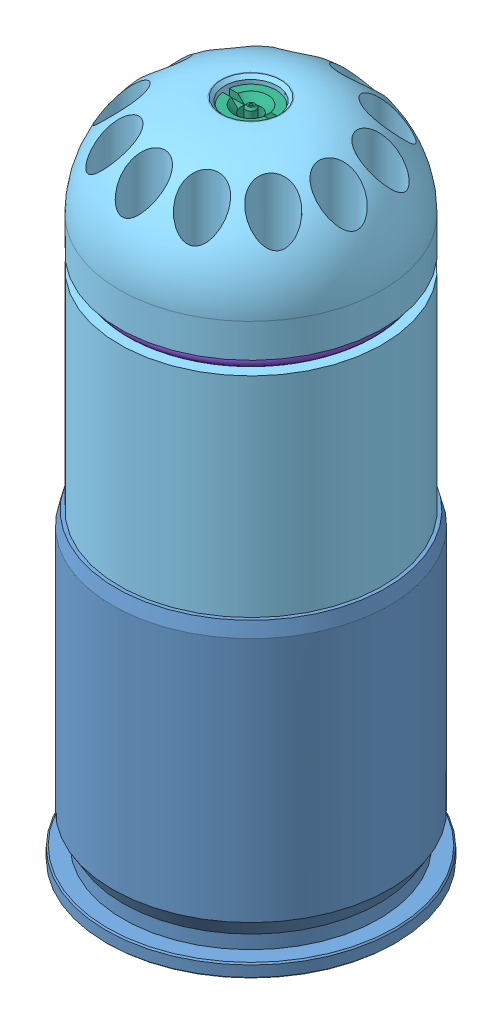
SolidWorks assembly 40mm-Klein, configuration Standard. Lengths in mm.
Overall size (51.21 98 51.21).
11 component instances, 8 part files, 20 mates.
Components (placement in the parent):
- Boden-G-1: Boden-G [Standard] at (-10.8436 -22.8172 45) size (43 45 43)
- Drücker-G-1: Drücker-G [Standard] at (-10.8436 -22.8172 45) size (14 23 14)
- value-1: value [Standard] at (-10.8436 -4.0172 45) size (20 21.5 20)
- Lock-Kugel-1: Lock-Kugel [Standard] at (-10.8436 -3.0172 55) size (4 4 4)
- Lock-Kugel-2: Lock-Kugel [Standard] at (-0.8436 -3.0172 45) size (4 4 4)
- Lock-Kugel-3: Lock-Kugel [Standard] at (-20.8436 -3.0172 45) size (4 4 4)
- Lock-Kugel-4: Lock-Kugel [Standard] at (-10.8436 -3.0172 35) size (4 4 4)
- Vorn-K-1: Vorn-K [Standard] at (-10.8436 5.6828 45) x (0.99501 0 0.099776) z (-0.099776 0 0.99501) size (39 69.5 39)
- Einfüllventil-1: Einfüllventil [Standard] at (-10.8436 61.6828 45) size (7.5 12.5 7.5)
- value-gegen-1: value-gegen [Standard] at (-10.8436 11.4828 45) x (1 0 -0.000025) z (0.000025 0 1) size (17.5 18.5 17.5)
- O-Ring oben-1: O-Ring oben [Standard] at (-10.8436 54.1828 45) x (-0.837169 0 -0.546944) z (-0.546944 0 0.837169) size (37 2 37)
Mates (geometry in assembly coordinates):
- Konzentrisch1: concentric anti-aligned: cylinder of Boden-G-1 through (-10.8436 -21.8172 45) axis (0 1 0) radius 7; cylinder of Drücker-G-1 through (-10.8436 -12.8172 45) axis (0 -1 0) radius 7
- Deckungsgleich1: coincident aligned: plane of Boden-G-1 through (-10.8436 -22.8172 45) normal (0 -1 0); plane of Drücker-G-1 through (-10.8436 -22.8172 45) normal (0 -1 0)
- Konzentrisch2: concentric: cylinder of value-1 through (-10.8436 -1.0172 35) axis (0 0 1) radius 2; sphere of Lock-Kugel-1
- Tangential2: tangent: curve of value-1; sphere of Lock-Kugel-1
- Konzentrisch3: concentric: cylinder of value-1 through (-20.8436 -1.0172 45) axis (1 0 0) radius 2; sphere of Lock-Kugel-2
- Tangential4: tangent: curve of value-1; sphere of Lock-Kugel-2
- Konzentrisch4: concentric: cylinder of value-1 through (-10.8436 -1.0172 35) axis (0 0 1) radius 2; sphere of Lock-Kugel-4
- Tangential6: tangent: curve of value-1; sphere of Lock-Kugel-4
- Konzentrisch5: concentric: cylinder of value-1 through (-20.8436 -1.0172 45) axis (1 0 0) radius 2; sphere of Lock-Kugel-3
- Tangential8: tangent: curve of value-1; sphere of Lock-Kugel-3
- Deckungsgleich2: coincident aligned: circle of Boden-G-1; cylinder of value-1 through (-10.8436 4.9828 45) axis (0 -1 0) radius 10
- Konzentrisch6: concentric anti-aligned: cylinder of Vorn-K-1 through (-10.8436 5.6828 45) axis (0 1 0) radius 2; cylinder of Einfüllventil-1 through (-10.8436 72.1828 45) axis (0 -1 0) radius 2
- Deckungsgleich3: coincident anti-aligned: plane of Vorn-K-1 through (-10.8436 72.1828 45) normal (0 1 0); plane of Einfüllventil-1 through (-10.8436 72.1828 45) normal (0 -1 0)
- Deckungsgleich4: coincident anti-aligned: plane of Vorn-K-1 through (-10.8436 13.4828 45) normal (0 -1 0); plane of value-gegen-1 through (-10.8436 13.4828 45) normal (0 1 0)
- Konzentrisch7: concentric aligned: cylinder of Vorn-K-1 through (-10.8436 62.6828 45) axis (0 -1 0) radius 7.5; cylinder of value-gegen-1 through (-10.8436 29.9828 45) axis (0 -1 0) radius 7.5
- Deckungsgleich5: coincident anti-aligned: plane of value-1 through (-10.8436 11.4828 45) normal (0 1 0); plane of value-gegen-1 through (-10.8436 11.4828 45) normal (0 -1 0)
- Konzentrisch8: concentric aligned: cylinder of value-1 through (-10.8436 17.4828 45) axis (0 -1 0) radius 4.95; cylinder of value-gegen-1 through (-10.8436 19.2828 45) axis (0 -1 0) radius 5
- Deckungsgleich6: coincident anti-aligned: plane of Boden-G-1 through (-10.8436 22.1828 45) normal (0 1 0); plane of Vorn-K-1 through (-10.8436 22.1828 45) normal (0 -1 0)
- Tangential9: tangent: plane of Vorn-K-1 through (-32.7123 53.1828 42.8071) normal (0 1 0); torus of O-Ring oben-1
- Tangential10: tangent: cylinder of Vorn-K-1 through (-10.8436 75.1828 45) axis (0 1 0) radius 16.5; torus of O-Ring oben-1
